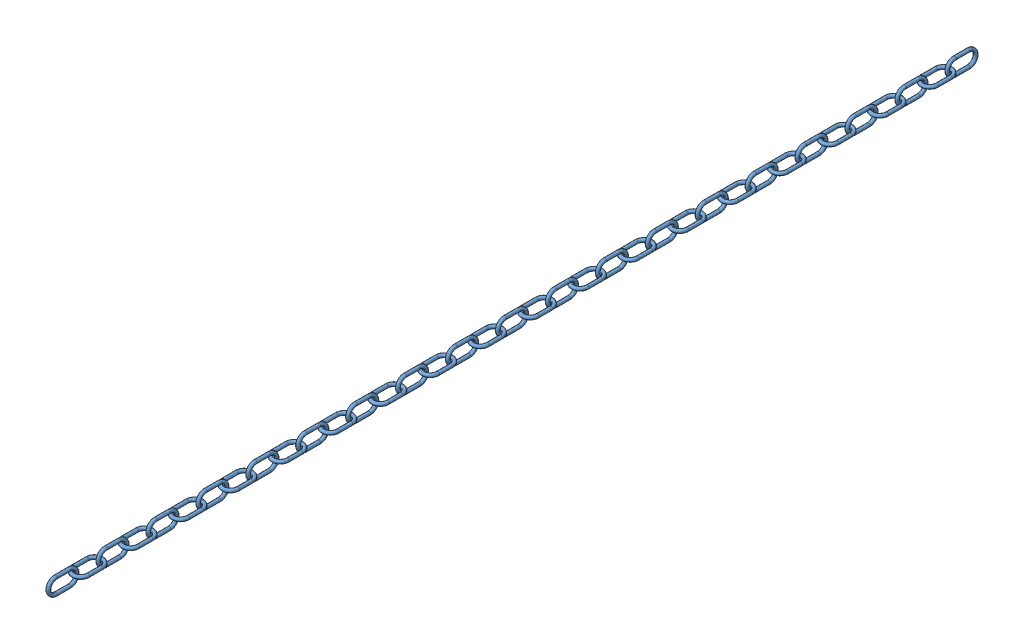
SolidWorks assembly GE-22355, configuration no u bolt. Lengths in mm.
Overall size (25.4 25.4 1301.75).
39 component instances, 2 part files, 9 mates.
Components (placement in the parent):
- GE-22355-01-1: GE-22355-01 [Default] at origin
- GE-22355-01-53: GE-22355-01 [Default] at (0 0 -34.925) x (0 1 0) z (0 0 1)
- GE-22355-01-19: GE-22355-01 [Default] at (0 0 -69.85)
- GE-22355-01-20: GE-22355-01 [Default] at (0 0 -139.7)
- GE-22355-01-21: GE-22355-01 [Default] at (0 0 -209.55)
- GE-22355-01-22: GE-22355-01 [Default] at (0 0 -279.4)
- GE-22355-01-23: GE-22355-01 [Default] at (0 0 -349.25)
- GE-22355-01-24: GE-22355-01 [Default] at (0 0 -419.1)
- GE-22355-01-25: GE-22355-01 [Default] at (0 0 -488.95)
- GE-22355-01-26: GE-22355-01 [Default] at (0 0 -558.8)
- GE-22355-01-27: GE-22355-01 [Default] at (0 0 -628.65)
- GE-22355-01-28: GE-22355-01 [Default] at (0 0 -698.5)
- GE-22355-01-29: GE-22355-01 [Default] at (0 0 -768.35)
- GE-22355-01-30: GE-22355-01 [Default] at (0 0 -838.2)
- GE-22355-01-31: GE-22355-01 [Default] at (0 0 -908.05)
- GE-22355-01-32: GE-22355-01 [Default] at (0 0 -977.9)
- GE-22355-01-33: GE-22355-01 [Default] at (0 0 -1047.75)
- GE-22355-01-54: GE-22355-01 [Default] at (0 0 -104.775) x (0 1 0) z (0 0 1)
- GE-22355-01-55: GE-22355-01 [Default] at (0 0 -174.625) x (0 1 0) z (0 0 1)
- GE-22355-01-56: GE-22355-01 [Default] at (0 0 -244.475) x (0 1 0) z (0 0 1)
- GE-22355-01-57: GE-22355-01 [Default] at (0 0 -314.325) x (0 1 0) z (0 0 1)
- GE-22355-01-58: GE-22355-01 [Default] at (0 0 -384.175) x (0 1 0) z (0 0 1)
- GE-22355-01-59: GE-22355-01 [Default] at (0 0 -454.025) x (0 1 0) z (0 0 1)
- GE-22355-01-60: GE-22355-01 [Default] at (0 0 -523.875) x (0 1 0) z (0 0 1)
- GE-22355-01-61: GE-22355-01 [Default] at (0 0 -593.725) x (0 1 0) z (0 0 1)
- GE-22355-01-62: GE-22355-01 [Default] at (0 0 -663.575) x (0 1 0) z (0 0 1)
- GE-22355-01-63: GE-22355-01 [Default] at (0 0 -733.425) x (0 1 0) z (0 0 1)
- GE-22355-01-64: GE-22355-01 [Default] at (0 0 -803.275) x (0 1 0) z (0 0 1)
- GE-22355-01-65: GE-22355-01 [Default] at (0 0 -873.125) x (0 1 0) z (0 0 1)
- GE-22355-01-66: GE-22355-01 [Default] at (0 0 -942.975) x (0 1 0) z (0 0 1)
- GE-22355-01-67: GE-22355-01 [Default] at (0 0 -1012.825) x (0 1 0) z (0 0 1)
- GE-22355-01-48: GE-22355-01 [Default] at (0 0 -1117.6)
- GE-22355-01-68: GE-22355-01 [Default] at (0 0 -1082.675) x (0 1 0) z (0 0 1)
- GE-22355-01-50: GE-22355-01 [Default] at (0 0 -1187.45)
- GE-22355-01-69: GE-22355-01 [Default] at (0 0 -1152.525) x (0 1 0) z (0 0 1)
- Ubolt_.25_.75_1.25-1: Ubolt_.25_.75_1.25 [3043T641] at (0 0 4.7625) x (-1 0 0) z (0 1 0) (suppressed, hidden)
- Ubolt_.25_.75_1.25-2: Ubolt_.25_.75_1.25 [3043T641] at (0 0 -1306.5125) x (-1 0 0) z (0 -1 0) (suppressed, hidden)
- GE-22355-01-52: GE-22355-01 [Default] at (0 0 -1257.3)
- GE-22355-01-70: GE-22355-01 [Default] at (0 0 -1222.375) x (0 1 0) z (0 0 1)
Mates (geometry in assembly coordinates):
- Coincident5: coincident anti-aligned: plane of low funnel chain-17 through (0 0 -1263.65) normal (0 0 -1)
- Coincident6: coincident anti-aligned: plane of low funnel chain-17 through (0 0 -1263.65) normal (0 -1 0)
- Coincident7: coincident aligned: plane of low funnel chain-17 through (0 0 -1263.65) normal (1 0 0)
- Coincident8: coincident anti-aligned: plane of low funnel chain-18 through (0 0 -34.925) normal (-1 0 0)
- Coincident9: coincident aligned: plane of low funnel chain-18 through (0 0 -34.925) normal (0 1 0)
- Distance1: distance = 34.925 mm: plane of assembly through (0 0 0) normal (0 0 1); plane of low funnel chain-18 through (0 0 -34.925) normal (0 0 1)
- Distance2: distance = 4.7625 mm aligned: plane of 3043T641_U-BOLT-1 through (0 0 -4.7625) normal (0 0 1)
- Coincident15: coincident anti-aligned: plane of 3043T641_U-BOLT-1 through (0 0 4.7625) normal (-1 0 0)
- Coincident17: coincident aligned: plane of 3043T641_U-BOLT-1 through (0 0 4.7625) normal (0 1 0)
